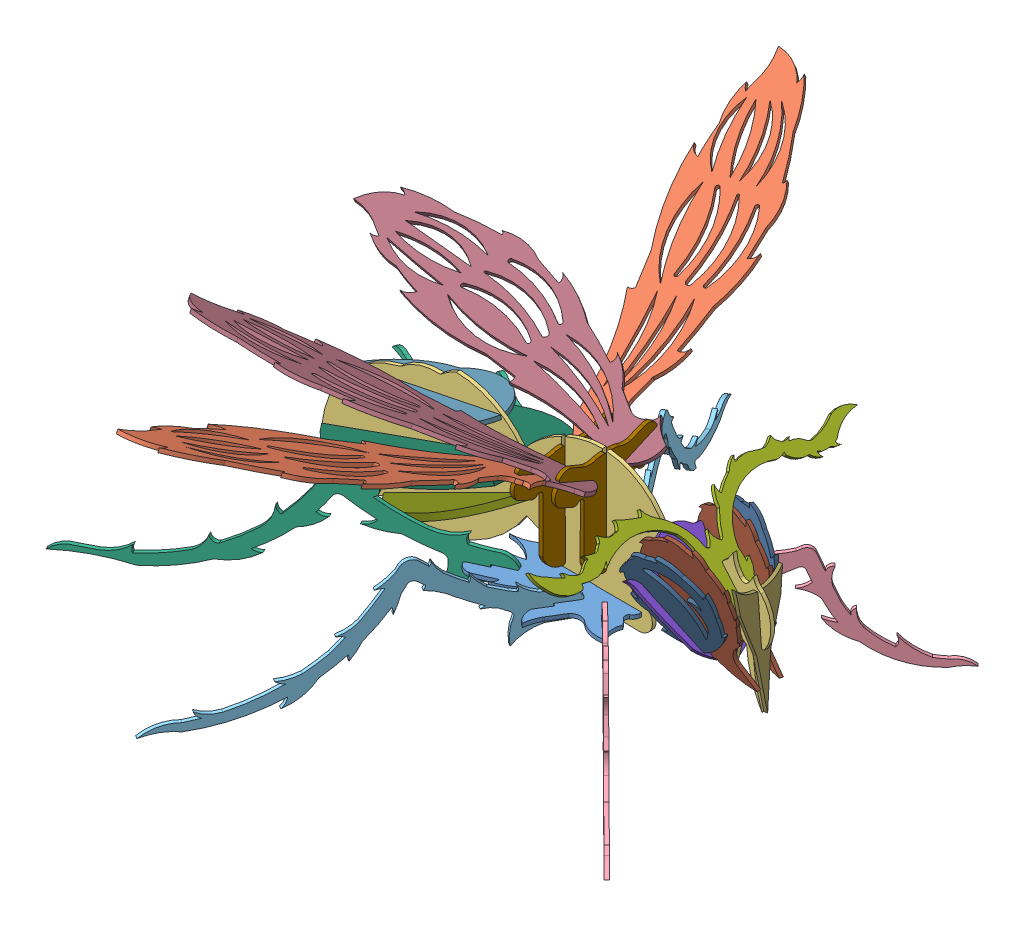
SolidWorks assembly _Assy, Hornet-01, configuration Default. Lengths in mm.
Overall size (235.5 199.58 277.86).
24 component instances, 16 part files, 51 mates.
Components (placement in the parent):
- Hornet, Pelvis-1: Hornet, Pelvis [Default] at (17.6168 31.2512 -31.0454) size (57.86 1.52 56.74)
- Hornet, Wing - 01-1: Hornet, Wing - 01 [Default] at (-10.0286 120.4289 99.2194) x (0.336637 -0.374446 -0.863982) z (-0.002469 0.91718 -0.398464) size (147.1 35.45 1.52)
- Hornet, Spine-1: Hornet, Spine [Default] at (45.1174 51.4743 -30.8501) x (0.764345 0.644805 -0.001475) z (-0.001929 0 -0.999998) size (152.02 132.86 1.52)
- Hornet, Leg, Small-1: Hornet, Leg, Small [Default] at (-171.012 575.3732 -229.8987) x (-0.705124 -0.133956 -0.696316) z (-0.702649 0 0.711537) size (87.41 46.78 1.52)
- Hornet, Leg, Med-1: Hornet, Leg, Med [Default] at (-1.3506 26.3342 25.3561) x (0.511556 -0.167911 -0.842684) z (-0.854821 0 -0.518923) size (123.6 60.75 1.52)
- Hornet, Leg, Big-1: Hornet, Leg, Big [Default] at (-56.7367 26.4997 8.1295) x (0.901202 -0.126817 -0.41443) z (-0.417803 0 -0.908537) size (137.37 58.77 1.52)
- Hornet, Antennae-1: Hornet, Antennae [Default] at (266.7402 -160.3188 904.5917) x (0.645404 -0.763841 -0.001243) z (0.763839 0.645405 -0.001474) size (42.79 127.21 1.52)
- Hornet, Face Plt-1: Hornet, Face Plt [Default] at (-122.938 282.3119 -480.4875) x (-0.353748 0.437147 0.826901) z (0.775973 0.630764 -0.001497) size (43.17 42.42 1.52)
- Hornet, Pelvis, Connector - 01-1: Hornet, Pelvis, Connector - 01 [Default] at (13.9177 59.4882 -28.1064) x (-0.001031 -0.398468 -0.917182) z (-0.999996 -0.001854 0.001929) size (40.22 46.84 1.52)
- Hornet, Face Plt, Eye-1: Hornet, Face Plt, Eye [Default] at (71.0811 55.7924 -18.4006) x (-0.891764 -0.446612 0.072767) z (0.198897 -0.242432 0.949561) size (28.93 36.7 1.52)
- Hornet, Face Plt, Eye-01-1: Hornet, Face Plt, Eye-01 [Default] at (73.8099 54.3829 -22.1906) x (0.981016 -0.16062 -0.108666) z (-0.091566 0.110296 -0.989672) size (45.03 37.72 1.52)
- Hornet, Stinger-1: Hornet, Stinger [Default] at (107.0155 -151.7089 230.2442) x (-0.075335 0.985211 -0.153893) z (-0.99711 -0.075944 0.001924) size (45.92 18.6 1.52)
- Hornet, Face Plt, Eye-2: Hornet, Face Plt, Eye [Default] at (71.3275 55.4229 -46.3719) x (-0.892038 -0.446612 -0.069325) z (-0.195232 0.242432 0.950322) size (28.93 36.7 1.52)
- Hornet, Face Plt, Eye-01-2: Hornet, Face Plt, Eye-01 [Default] at (73.6396 54.551 -39.6354) x (0.981428 -0.16062 0.104879) z (0.087746 -0.110296 -0.990018) size (45.03 37.72 1.52)
- Hornet, Pelvis, Connector - 01-2: Hornet, Pelvis, Connector - 01 [Default] at (30.2058 65.0894 -28.1379) x (-0.001031 -0.398466 -0.917183) z (-0.999996 -0.001854 0.001929) size (40.22 46.84 1.52)
- Hornet, Wing - 02-1: Hornet, Wing - 02 [Default] at (-90.6939 91.1365 19.4714) x (0.988085 -0.059083 -0.14212) z (-0.002469 0.917181 -0.398463) size (141.32 35.45 1.52)
- Hornet, Wing - 01-2: Hornet, Wing - 01 [Default] at (-10.5344 121.8267 -161.6225) x (0.339968 -0.374446 0.862677) z (0.000932 -0.91718 -0.398471) size (147.1 35.45 1.52)
- Hornet, Wing - 02-2: Hornet, Wing - 02 [Default] at (-90.8914 92.5343 -81.5638) x (0.988626 -0.059083 0.138306) z (0.000932 -0.917181 -0.398469) size (141.32 35.45 1.52)
- Hornet, Leg, Big-2: Hornet, Leg, Big [Default] at (-57.5206 26.4997 -69.5732) x (0.902794 -0.126817 0.41095) z (0.414295 0 -0.910143) size (137.37 58.77 1.52)
- Hornet, Leg, Med-2: Hornet, Leg, Med [Default] at (-2.8697 26.3342 -87.6047) x (0.514804 -0.167911 0.840704) z (0.852812 0 -0.522218) size (123.6 60.75 1.52)
- Hornet, Leg, Small-2: Hornet, Leg, Small [Default] at (-171.3203 575.3732 166.4268) x (-0.702432 -0.133956 0.699031) z (0.705389 0 0.70882) size (87.41 46.78 1.52)
- Hornet, Tail-01 Top-1: Hornet, Tail-01 Top [Default] at (39.0935 81.264 -30.8384) x (-0.980159 -0.198204 0.001891) z (-0.198204 0.980161 0.000382) size (59.87 32.67 1.52)
- Hornet, Tail-02 Mid-1: Hornet, Tail-02 Mid [Default] at (36.772 75.0143 -30.834) x (-0.94252 -0.334146 0.001818) z (-0.334145 0.942521 0.000645) size (98.33 51.61 1.52)
- Part3^_Assy, Hornet-01-1: Part3^_Assy, Hornet-01 [Default] at (37.2433 67.3104 -30.8349) x (-0.895417 -0.445225 0.001728) z (-0.445224 0.895419 0.000859) size (61.4 30.01 2.54) (virtual)
Mates (geometry in assembly coordinates):
- Coincident1: coincident anti-aligned: plane of Hornet, Pelvis-1 through (41.2279 32.7752 -32.803) normal (0 1 0); plane of Hornet, Leg, Small-1 through (46.2114 32.7752 -17.1014) normal (0 -1 0)
- Coincident2: coincident anti-aligned: plane of Hornet, Pelvis-1 through (45.7078 32.7752 -13.7442) normal (0.702649 0 -0.711537); plane of Hornet, Leg, Small-1 through (40.0628 122.0059 -19.3187) normal (-0.702649 0 0.711537)
- Coincident3: coincident: moEndPointRef_w of Hornet, Pelvis-1; plane of Hornet, Leg, Small-1 through (37.4435 31.2687 -21.5332) normal (-0.74011 0.000115 -0.672485)
- Coincident4: coincident anti-aligned: plane of Hornet, Pelvis-1 through (41.2279 32.7752 -32.803) normal (0 1 0); plane of Hornet, Leg, Med-1 through (26.785 32.7752 -23.9284) normal (0 -1 0)
- Coincident5: coincident anti-aligned: plane of Hornet, Pelvis-1 through (19.0875 32.7752 -11.2483) normal (0.854821 0 0.518923); plane of Hornet, Leg, Med-1 through (26.9157 30.5458 -24.1437) normal (-0.854821 0 -0.518923)
- Coincident6: coincident: moEndPointRef_w of Hornet, Pelvis-1; plane of Hornet, Leg, Med-1 through (22.7241 32.7752 -17.2389) normal (0.518923 0.000122 -0.854821)
- Coincident7: coincident anti-aligned: plane of Hornet, Pelvis-1 through (41.2279 32.7752 -32.803) normal (0 1 0); plane of Hornet, Leg, Big-1 through (4.556 32.7752 -21.7343) normal (0 -1 0)
- Coincident8: coincident anti-aligned: plane of Hornet, Pelvis-1 through (-9.3535 32.7752 -15.3378) normal (0.417803 0 0.908537); plane of Hornet, Leg, Big-1 through (2.1445 121.7385 -20.6253) normal (-0.417803 0 -0.908537)
- Coincident9: coincident: moEndPointRef_w of Hornet, Pelvis-1; plane of Hornet, Leg, Big-1 through (-2.553 32.7752 -18.4651) normal (0.908537 -0.000065 -0.417803)
- Coincident31: coincident anti-aligned: plane of Hornet, Pelvis-1 through (41.2279 32.7752 -32.803) normal (0 1 0); plane of Hornet, Spine-1 through (9.1983 32.7752 -32.3048) normal (0 -1 0)
- Coincident34: coincident anti-aligned: plane of Hornet, Spine-1 through (69.9032 48.5562 -32.4219) normal (-0.775973 -0.630764 0.001497); plane of Hornet, Face Plt-1 through (18.7432 111.9749 170.2511) normal (0.775973 0.630764 -0.001497)
- Coincident35: coincident anti-aligned: plane of Hornet, Spine-1 through (49.0202 35.6198 -30.8576) normal (0.001929 0 0.999998); plane of Hornet, Face Plt-1 through (69.9062 48.5561 -30.8979) normal (-0.001929 0 -0.999998)
- Coincident37: coincident: plane of Hornet, Spine-1 through (68.7341 47.6059 -32.4196) normal (-0.630758 0.775979 0.001217); moEndPointRef_w of Hornet, Face Plt-1
- Coincident51: coincident anti-aligned: plane of Hornet, Spine-1 through (75.0692 64.385 -32.4319) normal (0.763839 0.645405 -0.001474); plane of Hornet, Antennae-1 through (75.1757 64.3219 -4.8369) normal (-0.763839 -0.645405 0.001474)
- Coincident52: coincident anti-aligned: plane of Hornet, Spine-1 through (49.0172 35.6198 -32.3816) normal (-0.001929 0 -0.999998); plane of Hornet, Antennae-1 through (82.0259 58.513 -32.4453) normal (0.001929 0 0.999998)
- Coincident54: coincident: plane of Hornet, Spine-1 through (80.8616 57.5296 -32.443) normal (-0.645293 0.763934 0.001245); moEndPointRef_w of Hornet, Antennae-1
- Coincident61: coincident anti-aligned: plane of Hornet, Face Plt-1 through (69.933 48.5528 -18.4035) normal (-0.198897 0.242432 -0.949561); plane of Hornet, Face Plt, Eye-1 through (64.8863 61.3095 -14.0895) normal (0.198897 -0.242432 0.949561)
- Coincident62: coincident anti-aligned: plane of Hornet, Face Plt-1 through (18.7432 111.9749 170.2511) normal (0.775973 0.630764 -0.001497); plane of Hornet, Face Plt, Eye-1 through (69.933 48.5528 -18.4035) normal (-0.775973 -0.630764 0.001497)
- Coincident63: coincident: plane of Hornet, Face Plt-1 through (69.6334 48.918 -19.8341) normal (-0.598603 0.737152 0.313498); moEndPointRef_w of Hornet, Face Plt, Eye-1
- Coincident66: coincident anti-aligned: plane of Hornet, Face Plt-1 through (17.5606 111.0136 170.2533) normal (-0.775973 -0.630764 0.001497); plane of Hornet, Face Plt, Eye-01-1 through (66.3754 50.5013 -23.4752) normal (0.775973 0.630764 -0.001497)
- Coincident76: coincident anti-aligned: plane of Hornet, Spine-1 through (13.9355 45.5439 -32.3139) normal (-0.999996 -0.001854 0.001929); plane of Hornet, Pelvis, Connector - 01-1 through (13.9263 65.1846 -18.1995) normal (0.999996 0.001854 -0.001929)
- Coincident77: coincident anti-aligned: plane of Hornet, Spine-1 through (49.0202 35.6198 -30.8576) normal (0.001929 0 0.999998); plane of Hornet, Pelvis, Connector - 01-1 through (12.4144 45.5502 -30.787) normal (-0.001929 0 -0.999998)
- Coincident79: coincident: moEndPointRef_w of Hornet, Spine-1; plane of Hornet, Pelvis, Connector - 01-1 through (12.4129 45.5456 -31.549) normal (0.001866 -0.99998 0.005997)
- Coincident80: coincident anti-aligned: plane of Hornet, Wing - 01-1 through (0.1713 63.703 -35.2395) normal (-0.002469 0.91718 -0.398464); plane of Hornet, Pelvis, Connector - 01-1 through (12.3899 70.6134 -19.409) normal (0.002469 -0.91718 0.398464)
- Coincident81: coincident anti-aligned: plane of Hornet, Wing - 01-1 through (12.3807 67.0547 -27.6002) normal (0.999996 0.001854 -0.001929); plane of Hornet, Pelvis, Connector - 01-1 through (12.4023 65.1818 -18.1966) normal (-0.999996 -0.001854 0.001929)
- Coincident82: coincident: moEndPointRef_w of Hornet, Wing - 01-1; plane of Hornet, Pelvis, Connector - 01-1 through (12.3936 69.2337 -18.8096) normal (0.001031 0.398468 0.917182)
- Coincident83: coincident anti-aligned: plane of Hornet, Spine-1 through (90.2686 41.4476 -32.4612) normal (0.99711 0.075944 -0.001924); plane of Hornet, Stinger-1 through (88.7018 62.0759 -30.1721) normal (-0.99711 -0.075944 0.001924)
- Coincident84: coincident anti-aligned: plane of Hornet, Spine-1 through (49.0202 35.6198 -30.8576) normal (0.001929 0 0.999998); plane of Hornet, Stinger-1 through (89.4065 52.8047 -30.9355) normal (-0.001929 0 -0.999998)
- Coincident87: coincident: moEndPointRef_w of Hornet, Spine-1; plane of Hornet, Stinger-1 through (89.4065 52.8047 -30.9355) normal (-0.075944 0.997112 0.000015)
- Coincident88: coincident anti-aligned: plane of Hornet, Face Plt-1 through (57.1876 64.226 -21.0956) normal (0.091566 -0.110296 0.989672); plane of Hornet, Face Plt, Eye-01-1 through (73.2524 51.1447 -24.0398) normal (-0.091566 0.110296 -0.989672)
- Coincident90: coincident: moEndPointRef_w of Hornet, Face Plt-1; plane of Hornet, Face Plt, Eye-01-1 through (67.5441 51.4518 -23.4774) normal (0.624299 -0.767921 -0.143344)
- Coincident91: coincident anti-aligned: plane of Hornet, Pelvis-1 through (44.3905 32.7752 -32.3727) normal (0.001929 0 0.999998); plane of Hornet, Spine-1 through (49.0172 35.6198 -32.3816) normal (-0.001929 0 -0.999998)
- Coincident93: coincident: moEndPointRef_w of Hornet, Pelvis-1; plane of Hornet, Spine-1 through (26.3923 32.7752 -32.3379) normal (-0.999998 -0.00009 0.001929)
- Coincident94: coincident anti-aligned: plane of Hornet, Spine-1 through (28.6414 82.4968 -32.3423) normal (0.999996 0.001854 -0.001929); plane of Hornet, Pelvis, Connector - 01-2 through (28.6903 70.7829 -18.228) normal (-0.999996 -0.001854 0.001929)
- Coincident98: coincident: plane of Hornet, Spine-1 through (28.6995 51.1491 -32.3424) normal (-0.001854 0.999998 0.000004); moEndPointRef_w of Hornet, Pelvis, Connector - 01-2
- Coincident99: coincident anti-aligned: plane of Hornet, Spine-1 through (49.0172 35.6198 -32.3816) normal (-0.001929 0 -0.999998); plane of Hornet, Pelvis, Connector - 01-2 through (28.6995 51.1514 -32.3424) normal (0.001929 0 0.999998)
- Coincident100: coincident anti-aligned: plane of Hornet, Pelvis, Connector - 01-2 through (28.6779 76.2146 -19.4404) normal (0.002469 -0.917181 0.398463); plane of Hornet, Wing - 02-1 through (37.0895 58.8708 -59.4142) normal (-0.002469 0.917181 -0.398463)
- Coincident101: coincident anti-aligned: plane of Hornet, Pelvis, Connector - 01-2 through (28.6816 74.8349 -18.841) normal (0.001031 0.398466 0.917183); plane of Hornet, Wing - 02-1 through (28.6779 76.2146 -19.4404) normal (-0.001031 -0.398466 -0.917183)
- Coincident102: coincident anti-aligned: plane of Hornet, Pelvis, Connector - 01-2 through (30.2143 70.7858 -18.2309) normal (0.999996 0.001854 -0.001929); plane of Hornet, Wing - 02-1 through (30.1949 73.4878 -25.7262) normal (-0.999996 -0.001854 0.001929)
- InPlace1: in place: plane of Hornet, Spine-1 through (-80.3227 57.1167 -32.1321) normal (-0.198204 0.980161 0.000382); plane of ? through (-14.2492 70.4652 0.0275) normal (-0.198204 0.980161 0.000382); moOrthogonalPlaneRef_w of Hornet, Spine-1 through (-80.3227 57.1167 -32.1321) normal (-0.198204 0.980161 0.000382); unknown of ?; plane of Hornet, Spine-1 through (-80.3227 57.1167 -32.1321) normal (-0.198204 0.980161 0.000382); unknown of ?; plane of Hornet, Spine-1 through (-80.3227 57.1167 -32.1321) normal (-0.198204 0.980161 0.000382); unknown of Hornet, Tail-01 Top-1
- Coincident103: coincident aligned: plane of Hornet, Spine-1; plane of Hornet, Tail-01 Top-1
- Coincident104: coincident aligned: moOrthogonalPlaneRef_w of Hornet, Spine-1 through (39.0935 81.264 -30.8384) normal (0.001929 0 0.999998); plane of Hornet, Tail-01 Top-1
- Coincident105: coincident anti-aligned: moOrthogonalPlaneRef_w of Hornet, Spine-1 through (39.0935 81.264 -30.8384) normal (0.980159 0.198204 -0.001891); plane of Hornet, Tail-01 Top-1
- InPlace2: in place: plane of Hornet, Spine-1 through (-86.4689 31.3235 -32.1202) normal (-0.334145 0.942521 0.000645); plane of ? through (-19.5126 55.039 0.0376) normal (-0.334145 0.942521 0.000645); plane of Hornet, Spine-1 through (-86.4689 31.3235 -32.1202) normal (-0.334145 0.942521 0.000645); unknown of ?; plane of Hornet, Spine-1 through (-86.4689 31.3235 -32.1202) normal (-0.334145 0.942521 0.000645); unknown of ?; plane of Hornet, Spine-1 through (-86.4689 31.3235 -32.1202) normal (-0.334145 0.942521 0.000645); unknown of Hornet, Tail-02 Mid-1
- Coincident106: coincident aligned: plane of Hornet, Spine-1; plane of Hornet, Tail-02 Mid-1
- Coincident107: coincident aligned: moOrthogonalPlaneRef_w of Hornet, Spine-1 through (36.772 75.0143 -30.834) normal (0.001929 0 0.999998); plane of Hornet, Tail-02 Mid-1
- Coincident108: coincident anti-aligned: moOrthogonalPlaneRef_w of Hornet, Spine-1 through (36.772 75.0143 -30.834) normal (0.94252 0.334146 -0.001818); plane of Hornet, Tail-02 Mid-1
- InPlace3: in place: plane of Hornet, Spine-1 through (-62.3808 17.7762 -32.1667) normal (-0.445224 0.895419 0.000859); plane of ? through (-19.4398 39.0966 0.0375) normal (-0.445224 0.895419 0.000859); plane of Hornet, Spine-1 through (-62.3808 17.7762 -32.1667) normal (-0.445224 0.895419 0.000859); unknown of ?; plane of Hornet, Spine-1 through (-62.3808 17.7762 -32.1667) normal (-0.445224 0.895419 0.000859); unknown of ?; plane of Hornet, Spine-1 through (-62.3808 17.7762 -32.1667) normal (-0.445224 0.895419 0.000859); unknown of Part3^_Assy, Hornet-01-1
- Coincident109: coincident aligned: plane of Hornet, Spine-1; plane of Part3^_Assy, Hornet-01-1
- Coincident110: coincident aligned: moOrthogonalPlaneRef_w of Hornet, Spine-1 through (37.2433 67.3104 -30.8349) normal (0.001929 0 0.999998); plane of Part3^_Assy, Hornet-01-1
- Coincident111: coincident anti-aligned: moOrthogonalPlaneRef_w of Hornet, Spine-1 through (37.2433 67.3104 -30.8349) normal (0.895417 0.445225 -0.001728); plane of Part3^_Assy, Hornet-01-1
